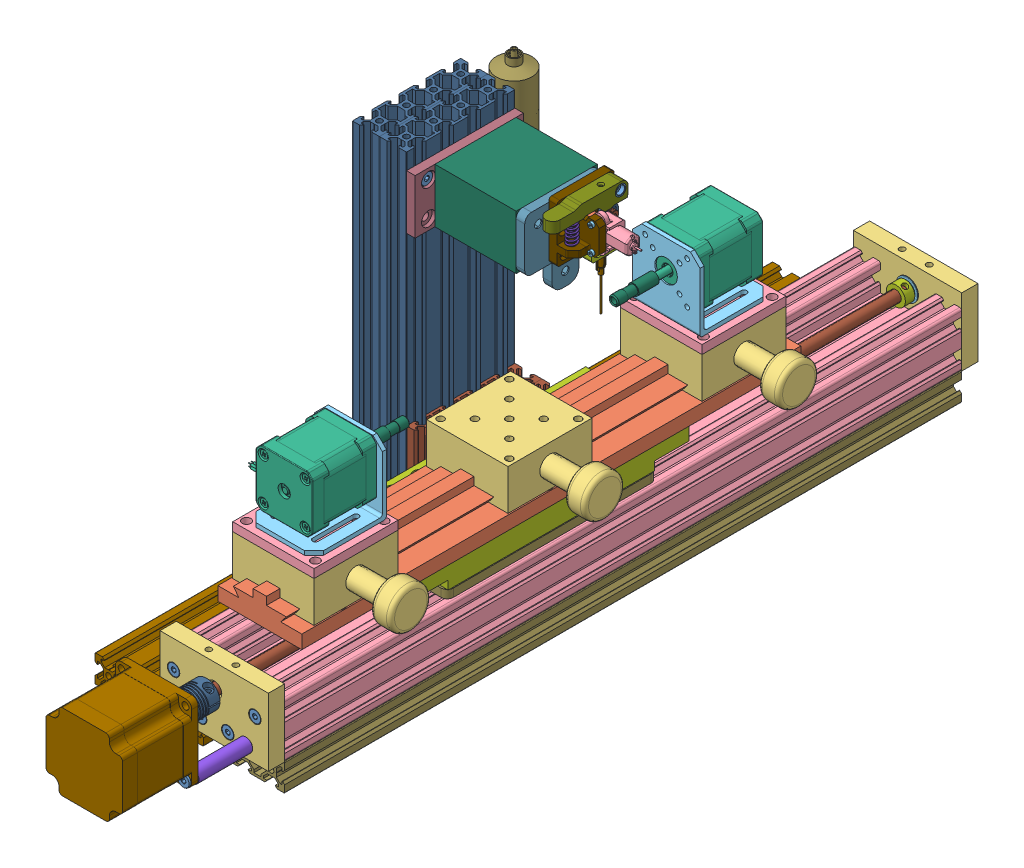
SolidWorks assembly LathePrinter, configuration Default. Lengths in mm.
Overall size (197.6 251.58 620.07).
127 component instances, 54 part files, 33 mates.
Components (placement in the parent):
- C-Beam Doublewide Linear Actuator 500mm-1: C-Beam Doublewide Linear Actuator 500mm [Default] at origin size (80 60.67 620.07)
  - Low Profile Screw M5-3: Low Profile Screw M5 [M5 x 20] at (56.4477 48.3418 46.5759) x (0 0 -1) z (1 0 0) size (21.62 9 9)
  - Low Profile Screw M5-4: Low Profile Screw M5 [M5 x 20] at (36.4477 28.3418 46.5759) x (0 0 -1) z (1 0 0) size (21.62 9 9)
  - Low Profile Screw M5-5: Low Profile Screw M5 [M5 x 20] at (16.4477 28.3418 46.5759) x (0 0 -1) z (1 0 0) size (21.62 9 9)
  - Low Profile Screw M5-6: Low Profile Screw M5 [M5 x 20] at (-3.5523 48.3418 46.5759) x (0 0 -1) z (1 0 0) size (21.62 9 9)
  - Low Profile Screw M5-7: Low Profile Screw M5 [M5 x 20] at (56.4477 48.3418 -434.3241) x (0 0 1) z (-1 0 0) size (21.62 9 9)
  - Low Profile Screw M5-8: Low Profile Screw M5 [M5 x 20] at (36.4477 28.3418 -434.3241) x (0 0 1) z (-1 0 0) size (21.62 9 9)
  - Low Profile Screw M5-9: Low Profile Screw M5 [M5 x 20] at (16.4477 28.3418 -434.3241) x (0 0 1) z (-1 0 0) size (21.62 9 9)
  - Low Profile Screw M5-10: Low Profile Screw M5 [M5 x 20] at (-3.5523 48.3418 -434.3241) x (0 0 1) z (-1 0 0) size (21.62 9 9)
  - Nylon Insert Lock Nut M5-1: Nylon Insert Lock Nut M5 [Default] at (36.4477 49.7418 -147.7451) x (0.5 0 0.866025) z (0.866025 0 -0.5) size (8 5 9.24)
  - Nylon Insert Lock Nut M5-2: Nylon Insert Lock Nut M5 [Default] at (16.4477 49.7418 -147.7451) x (-0.5 0 0.866025) z (0.866025 0 0.5) size (8 5 9.24)
  - Low Profile Screw M5-11: Low Profile Screw M5 [M5 x 20] at (16.4477 44.5418 -147.7451) x (0 -1 0) z (0 0 1) size (21.62 9 9)
  - Low Profile Screw M5-12: Low Profile Screw M5 [M5 x 20] at (36.4477 44.5418 -147.7451) x (0 -1 0) z (0 0 1) size (21.62 9 9)
  - Low Profile Screw M5-13: Low Profile Screw M5 [M5 x 25] at (40.6977 39.5418 -191.4751) x (0 -1 0) z (-0.551688 0 0.834051) size (26.62 9 9)
  - Low Profile Screw M5-14: Low Profile Screw M5 [M5 x 25] at (40.6977 39.5418 -93.9651) x (0 -1 0) z (-0.031752 0 0.999496) size (26.62 9 9)
  - Low Profile Screw M5-15: Low Profile Screw M5 [M5 x 25] at (12.1977 39.5418 -192.2651) x (0 -1 0) z (-0.003762 0 0.999993) size (26.62 9 9)
  - Low Profile Screw M5-16: Low Profile Screw M5 [M5 x 25] at (12.1977 39.5418 -93.1751) x (0 -1 0) z (-0.030252 0 0.999542) size (26.62 9 9)
  - Low Profile Screw M5-17: Low Profile Screw M5 [M5 x 55] at (50.0177 27.2418 57.9259) x (0 0 -1) z (1 0 0) size (56.62 9 9)
  - Low Profile Screw M5-18: Low Profile Screw M5 [M5 x 55] at (2.8777 27.2418 57.9259) x (0 0 -1) z (1 0 0) size (56.62 9 9)
  - C-Beam End Mount-1: C-Beam End Mount [Default] at (-13.5523 18.3418 56.1259) size (80 50 12)
  - C-Beam 40x80x500 Linear Rail-1: C-Beam 40x80x500 Linear Rail [Default] at (26.4477 38.3418 -443.8741) x (0 1 0) z (0 0 1) size (40 80 500)
  - C-Beam End Mount-2: C-Beam End Mount [Default] at (66.4477 18.3418 -443.8741) x (-1 0 0) z (0 0 -1) size (80 50 12)
  - Ball Bearing 8 x 16 x 5-1: Ball Bearing 8 x 16 x 5 [Default] at (26.4477 50.7418 -445.8741) x (0 0 1) z (-0.834564 -0.55091 0) size (5 16 16)
  - Ball Bearing 8 x 16 x 5-2: Ball Bearing 8 x 16 x 5 [Default] at (26.4477 50.7418 58.1259) x (0 0 -1) z (0.759688 -0.650288 0) size (5 16 16)
  - Shim Washer 8mm-1: Shim Washer 8mm [Default] at (26.4477 50.7418 -443.3741) x (0.747547 0.664209 0) z (0.664209 -0.747547 0) size (11.8 1.15 11.8)
  - Shim Washer 8mm-2: Shim Washer 8mm [Default] at (26.4477 50.7418 54.4759) x (0.999066 -0.043208 0) z (-0.043208 -0.999066 0) size (11.8 1.15 11.8)
  - Lock Collar 8mm-1: Lock Collar 8mm [Default] at (26.4477 50.7418 -442.2241) x (0.884083 -0.467331 0) z (0 0 1) size (14 14 7)
  - Lock Collar 8mm-2: Lock Collar 8mm [Default] at (26.4477 50.7418 47.4759) x (0.923513 -0.383568 0) z (0 0 1) size (14 14 7)
  - Aluminum Spacer 40mm-1: Aluminum Spacer 40mm [Default] at (2.8777 27.2418 68.1259) size (10 10 40)
  - Aluminum Spacer 40mm-2: Aluminum Spacer 40mm [Default] at (50.0177 27.2418 68.1259) x (0.999611 0.027877 0) z (0 0 1) size (10 10 40)
  - Nema 23 Stepper Motor-1: Nema 23 Stepper Motor [Default] at (26.4477 50.8118 108.1259) x (-1 0 0) z (0 0 -1) size (56.4 56.4 76.6)
  - Flexible Coupling 0.25in x 8mm-1: Flexible Coupling 0.25in x 8mm [Default] at (26.4477 50.8118 98.5259) size (21.03 20 25)
  - 8mm leadscrew 540mm-1: 8mm leadscrew 540mm [Default] at (26.4477 50.7418 -455.8741) size (8 8 540)
  - Double CB-Gantry Plate-1: Double CB-Gantry Plate [Default] at (65.2077 60.0418 -65.2101) x (0 0 -1) z (1 0 0) size (155.02 6 77.52)
  - 8mm Acme Nut Block-1: 8mm Acme Nut Block [Default] at (26.4477 50.7418 -137.7451) x (1 0 0) z (0 0 -1) size (34 12 20)
  - Xtreme Mini V Wheel-1: Xtreme Mini V Wheel [Straight] at (40.6977 48.3418 -93.9651) x (0.579004 0 0.815325) z (-0.815325 0 0.579004) size (15.23 23.9 15.23)
    - Xtreme Mini V Wheel-1: Xtreme Mini V Wheel [Default] x (0 -1 0) z (0 0 1) size (8.8 15.23 15.23)
    - Ball Bearing 5 x 10 x 4.2-1: Ball Bearing 5 x 10 x 4.2 [Default] at (0 -2.6 0) x (0 -1 0) z (0.990411 0 0.138155) size (4.2 10 10)
    - Ball Bearing 5 x 10 x 4.2-2: Ball Bearing 5 x 10 x 4.2 [Default] at (0 2.6 0) x (0 1 0) z (-0.887666 0 -0.460488) size (4.2 10 10)
    - Precision Shim 8 x 5 x 1-1: Precision Shim 8 x 5 x 1 [Default] at (0 -0.5 0) x (0.977063 0 -0.212952) z (0.212952 0 0.977063) size (8 1 8)
    - Precision Shim 8 x 5 x 1-2: Precision Shim 8 x 5 x 1 [Default] at (0 4.7 0) x (0.633048 0 -0.774113) z (0.774113 0 0.633048) size (8 1 8)
    - Nylon Insert Lock Nut M5-1: Nylon Insert Lock Nut M5 [Default] at (0 -4.7 0) x (-0.212185 0 -0.97723) z (-0.97723 0 0.212185) size (8 5 9.24)
    - Mini Eccentric Spacer 6mm-1: Mini Eccentric Spacer 6mm [Default] at (-0.79 10.7 0) x (0 0 1) z (1 0 0) size (10 8.5 9.7)
    - Aluminum Spacer 6mm-1: Aluminum Spacer 6mm [Default] at (0 11.7 0) x (-0.695188 0 0.718828) z (0 -1 0) size (10 10 6)
  - Xtreme Mini V Wheel-2: Xtreme Mini V Wheel [Straight] at (40.6977 48.3418 -191.4751) x (0.579004 0 0.815325) z (-0.815325 0 0.579004) size (15.23 23.9 15.23)
    - Xtreme Mini V Wheel-1: Xtreme Mini V Wheel [Default] x (0 -1 0) z (0 0 1) size (8.8 15.23 15.23)
    - Ball Bearing 5 x 10 x 4.2-1: Ball Bearing 5 x 10 x 4.2 [Default] at (0 -2.6 0) x (0 -1 0) z (0.990411 0 0.138155) size (4.2 10 10)
    - Ball Bearing 5 x 10 x 4.2-2: Ball Bearing 5 x 10 x 4.2 [Default] at (0 2.6 0) x (0 1 0) z (-0.887666 0 -0.460488) size (4.2 10 10)
    - Precision Shim 8 x 5 x 1-1: Precision Shim 8 x 5 x 1 [Default] at (0 -0.5 0) x (0.977063 0 -0.212952) z (0.212952 0 0.977063) size (8 1 8)
    - Precision Shim 8 x 5 x 1-2: Precision Shim 8 x 5 x 1 [Default] at (0 4.7 0) x (0.633048 0 -0.774113) z (0.774113 0 0.633048) size (8 1 8)
    - Nylon Insert Lock Nut M5-1: Nylon Insert Lock Nut M5 [Default] at (0 -4.7 0) x (-0.212185 0 -0.97723) z (-0.97723 0 0.212185) size (8 5 9.24)
    - Mini Eccentric Spacer 6mm-1: Mini Eccentric Spacer 6mm [Default] at (-0.79 10.7 0) x (0 0 1) z (1 0 0) size (10 8.5 9.7)
    - Aluminum Spacer 6mm-1: Aluminum Spacer 6mm [Default] at (0 11.7 0) x (-0.695188 0 0.718828) z (0 -1 0) size (10 10 6)
  - Xtreme Mini V Wheel-3: Xtreme Mini V Wheel [Eccentric] at (12.1977 48.3418 -93.1751) x (0 0 1) z (-1 0 0) size (15.23 23.9 15.23)
    - Xtreme Mini V Wheel-1: Xtreme Mini V Wheel [Default] x (0 -1 0) z (0 0 1) size (8.8 15.23 15.23)
    - Ball Bearing 5 x 10 x 4.2-1: Ball Bearing 5 x 10 x 4.2 [Default] at (0 -2.6 0) x (0 -1 0) z (0.990411 0 0.138155) size (4.2 10 10)
    - Ball Bearing 5 x 10 x 4.2-2: Ball Bearing 5 x 10 x 4.2 [Default] at (0 2.6 0) x (0 1 0) z (-0.887666 0 -0.460488) size (4.2 10 10)
    - Precision Shim 8 x 5 x 1-1: Precision Shim 8 x 5 x 1 [Default] at (0 -0.5 0) x (0.977063 0 -0.212952) z (0.212952 0 0.977063) size (8 1 8)
    - Precision Shim 8 x 5 x 1-2: Precision Shim 8 x 5 x 1 [Default] at (0 4.7 0) x (0.633048 0 -0.774113) z (0.774113 0 0.633048) size (8 1 8)
    - Nylon Insert Lock Nut M5-1: Nylon Insert Lock Nut M5 [Default] at (0 -4.7 0) x (-0.212185 0 -0.97723) z (-0.97723 0 0.212185) size (8 5 9.24)
    - Mini Eccentric Spacer 6mm-1: Mini Eccentric Spacer 6mm [Default] at (-0.79 10.7 0) x (0 0 1) z (1 0 0) size (10 8.5 9.7)
    - Aluminum Spacer 6mm-1: Aluminum Spacer 6mm [Default] at (0 11.7 0) x (-0.695188 0 0.718828) z (0 -1 0) size (10 10 6)
  - Xtreme Mini V Wheel-4: Xtreme Mini V Wheel [Eccentric] at (12.1977 48.3418 -192.2651) x (0 0 -1) z (1 0 0) size (15.23 23.9 15.23)
    - Xtreme Mini V Wheel-1: Xtreme Mini V Wheel [Default] x (0 -1 0) z (0 0 1) size (8.8 15.23 15.23)
    - Ball Bearing 5 x 10 x 4.2-1: Ball Bearing 5 x 10 x 4.2 [Default] at (0 -2.6 0) x (0 -1 0) z (0.990411 0 0.138155) size (4.2 10 10)
    - Ball Bearing 5 x 10 x 4.2-2: Ball Bearing 5 x 10 x 4.2 [Default] at (0 2.6 0) x (0 1 0) z (-0.887666 0 -0.460488) size (4.2 10 10)
    - Precision Shim 8 x 5 x 1-1: Precision Shim 8 x 5 x 1 [Default] at (0 -0.5 0) x (0.977063 0 -0.212952) z (0.212952 0 0.977063) size (8 1 8)
    - Precision Shim 8 x 5 x 1-2: Precision Shim 8 x 5 x 1 [Default] at (0 4.7 0) x (0.633048 0 -0.774113) z (0.774113 0 0.633048) size (8 1 8)
    - Nylon Insert Lock Nut M5-1: Nylon Insert Lock Nut M5 [Default] at (0 -4.7 0) x (-0.212185 0 -0.97723) z (-0.97723 0 0.212185) size (8 5 9.24)
    - Mini Eccentric Spacer 6mm-1: Mini Eccentric Spacer 6mm [Default] at (-0.79 10.7 0) x (0 0 1) z (1 0 0) size (10 8.5 9.7)
    - Aluminum Spacer 6mm-1: Aluminum Spacer 6mm [Default] at (0 11.7 0) x (-0.695188 0 0.718828) z (0 -1 0) size (10 10 6)
  - Aluminum Spacer 3mm-1: Aluminum Spacer 3mm [Default] at (36.4477 57.0418 -147.7451) x (0.737978 0 0.674825) z (0 1 0) size (10 10 3)
  - Aluminum Spacer 3mm-2: Aluminum Spacer 3mm [Default] at (16.4477 57.0418 -147.7451) x (0.756365 0 -0.654149) z (0 1 0) size (10 10 3)
- Z Carriage Assembly-1: Z Carriage Assembly [Default] at (324.4062 -89.9257 -277.865) x (0 0 1) z (-1 0 0) size (368.5 98.11 101.5)
  - Edmund Optics Linear Bearing-1: Edmund Optics Linear Bearing [Default] at (-49.1052 171.8424 290.8585) size (368.5 21.1 62)
  - Edmund Optics Knob Stage-1: Edmund Optics Knob Stage [Default] at (-8.1052 211.8424 290.8585) x (0 0 -1) z (0 -1 0) size (100.5 62 30)
  - Edmund Optics Knob Stage-4: Edmund Optics Knob Stage [Default] at (135.1448 211.8424 290.8585) x (0 0 -1) z (0 -1 0) size (100.5 62 30)
  - Edmund Optics Knob Stage-5: Edmund Optics Knob Stage [Default] at (278.3948 211.8424 290.8585) x (0 0 -1) z (0 -1 0) size (100.5 62 30)
  - Mandrel Motor Plate-1: Mandrel Motor Plate [Default] at (278.3948 211.8424 290.8585) x (0 0 -1) z (0 1 0) size (60 62 6.35)
  - Mandrel Motor Plate-2: Mandrel Motor Plate [Default] at (-8.1052 211.8424 290.8585) x (0 0 -1) z (0 1 0) size (60 62 6.35)
  - Mandrel Motor Bracket-1: Mandrel Motor Bracket [Default] at (250.8948 218.1924 265.8585) size (53.5 51.5 50)
  - Mandrel Motor Bracket-2: Mandrel Motor Bracket [Default] at (19.3948 218.1924 315.8585) x (-1 0 0) z (0 0 -1) size (53.5 51.5 50)
  - NEMA17 Stepper-1: NEMA17 Stepper [По умолчанию] at (301.3948 235.6273 292.556) x (0 0.999984 -0.005702) z (0 0.005702 0.999984) size (42.19 71.6 51.3)
  - NEMA17 Stepper-2: NEMA17 Stepper [По умолчанию] at (-31.1052 261.7575 292.556) x (0 -0.999984 -0.005702) z (0 -0.005702 0.999984) size (42.19 71.6 51.3)
- Z Axis Plate-1: Z Axis Plate [Default] at (26.4477 66.0418 -142.7201) x (0 0 1) z (-1 0 0) size (203.2 15.88 76.2)
- 94855A247_LOW-STRENGTH STEEL SQUARE NUT-1: 94855A247_LOW-STRENGTH STEEL SQUARE NUT [94855A247] at (8.1553 70.0105 -141.8396) x (0.999789 0 0.020564) z (-0.020564 0 0.999789) size (11.11 5.74 11.11)
- Aluminum Extrusion Frame-1: Aluminum Extrusion Frame [Default] at (-183.5863 -1.6582 -193.8741) x (0 0 -1) z (1 0 0) size (500 245 160)
  - V-Slot 20x80x500 Linear Rail-1: V-Slot 20x80x500 Linear Rail [Default] at (250 10 150.034) x (0 -1 0) z (-1 0 0) size (20 80 500)
  - V-Slot 20x80x225 Linear Rail-2: V-Slot 20x80x225 Linear Rail [Default] at (0 245 100.034) x (0 0 1) z (0 -1 0) size (20 80 225)
  - V-Slot 20x80x225 Linear Rail-3: V-Slot 20x80x225 Linear Rail [Default] at (0 245 120.034) x (0 0 1) z (0 -1 0) size (20 80 225)
  - V-Slot 20x80x50 Linear Rail-4: V-Slot 20x80x50 Linear Rail [Default] at (0 70 140.034) x (0 0 1) z (0 -1 0) size (20 80 50)
  - V-Slot 20x40x500 Linear Rail-1: V-Slot 20x40x500 Linear Rail [Default] at (250 10 230.034) x (0 1 0) z (-1 0 0) size (20 40 500)
  - V-Slot 20x80x50 Linear Rail-5: V-Slot 20x80x50 Linear Rail [Default] at (0 70 160.034) x (0 0 1) z (0 -1 0) size (20 80 50)
- X Axis Plate-1: X Axis Plate [Default] at (-53.5523 211.4905 -193.8741) x (0 0 1) z (0 1 0) size (80 6.35 40)
- Low Profile Screw M5-1: Low Profile Screw M5 [M5 x 20] at (-69.9523 223.9905 -163.8741) x (-1 0 0) z (0 0.410028 -0.912073) size (21.62 9 9)
- Low Profile Screw M5-2: Low Profile Screw M5 [M5 x 20] at (56.4477 56.8168 -93.9651) x (0 -1 0) z (0 0 1) size (21.62 9 9)
- Nozzle Plate-1: Nozzle Plate [Captive nuts] at (12.7977 191.4905 -168.4783) x (0 0 -1) z (1 0 0) size (60 60 6.35)
- Optics XZ Manual Stage Placeholder-1: Optics XZ Manual Stage Placeholder [Default] at (-47.2023 211.4905 -193.8741) x (0 0 1) z (1 0 0) size (60 40 60)
- Experimental Extruder Dual Extruder-1: Experimental Extruder Dual Extruder [Default] at (19.1477 213.6163 -207.3751) x (0 0 -1) z (1 0 0) size (131.31 82.59 47.28)
  - ExtruderCR10 lever mirrored-1: ExtruderCR10 lever mirrored [Default] at (-21 -21 2) size (55.67 26.5 10.5)
  - ExtruderCR10 spring-1: ExtruderCR10 spring [Default] at (-21 -21 1.5) size (8.03 21.41 8.04)
  - Extruder custom base mirrored-1: Extruder custom base mirrored [Default] at origin size (42 42 26)
  - ExtruderCR10 bushing-1: ExtruderCR10 bushing [Default] at (-21 -21 2) size (8 8 10.5)
  - SLA Printed Driver-1: SLA Printed Driver [Default] at (0 0 -17.7668) size (11.5 11.5 6)
  - 52335K910 TUBING MADE WITH PTFE cut to size-1: 52335K910 TUBING MADE WITH PTFE cut to size [52335K91] at (6.35 -9.5 11) x (0 1 0) z (0.546944 0 -0.837169) size (15 3 3)
  - micro-metal-gearmotor-extended-with-1086-bracket (1)-1: micro-metal-gearmotor-extended-with-1086-bracket (1) [Default] at (0 0 26.27) x (0 0 -1) z (0 -1 0) size (39.3 11.72 26.5)
  - 91290A015_BLACK-OXIDE CLASS 12.9 SOCKET HEAD CAP SCREW-1: 91290A015_BLACK-OXIDE CLASS 12.9 SOCKET HEAD CAP SCREW [91290A015] at (-2 -9 21.2) x (0 -0.941673 -0.336529) z (1 0 0) size (3.8 3.8 10.11)
  - 91290A015_BLACK-OXIDE CLASS 12.9 SOCKET HEAD CAP SCREW-2: 91290A015_BLACK-OXIDE CLASS 12.9 SOCKET HEAD CAP SCREW [91290A015] at (-2 9 21.2) x (0 -0.660306 0.750996) z (1 0 0) size (3.8 3.8 10.11)
  - 91828A111_TYPE 18-8 STAINLESS STEEL HEX NUT-1: 91828A111_TYPE 18-8 STAINLESS STEEL HEX NUT [91828A111] at (-2.8 9 21.2) x (0 0 1) z (-1 0 0) size (4 4.62 1.83)
  - SLA Printed Manifold-1: SLA Printed Manifold [Default] at origin size (27 14.5 10.5)
  - Luer male print with manifold-2: Luer male print with manifold [Default] at (17.8808 -9.5965 11) x (0.923028 0.384734 0) z (0 0 1) size (8.55 9.27 9.27)
  - Luer male print with manifold-3: Luer male print with manifold [Default] at (6.35 -25.5471 11) x (0 -1 0) z (0 0 1) size (8.55 9.27 9.27)
  - Syringe Needle, With Luer-2: Syringe Needle, With Luer [Yellow_20Gauge] at (6.35 -36.1851 11) x (0 1 0) z (0 0 1) size (43.15 7.7 8.15)
  - MirrorExtruder custom base-2: MirrorExtruder custom base [Default] at (62 0 0) x (-1 0 0) z (0 0 -1) size (42 42 26) (hidden)
  - MirrorExtruderCR10 lever-2: MirrorExtruderCR10 lever [Default] at (83 -21 2) x (-1 0 0) z (0 0 -1) size (55.67 26.5 10.5) (hidden)
  - ExtruderCR10 bushing-2: ExtruderCR10 bushing [Default] at (10 -21 2) size (8 8 10.5) (hidden)
  - Luer male print with manifold-5: Luer male print with manifold [Default] at (44.1192 -9.5965 11) x (-0.923028 0.384734 0) z (0 0 1) size (8.55 9.27 9.27) (hidden)
  - MirrorPart21-2: MirrorPart21 [Default] at (62 0 0) x (-1 0 0) z (0 0 -1) size (27 14.5 10.5) (hidden)
  - Luer male print with manifold-6: Luer male print with manifold [Default] at (55.65 -25.5471 11) x (0 -1 0) z (0 0 -1) size (8.55 9.27 9.27) (hidden)
  - 7804K102_STAINLESS STEEL BALL BEARING-1: 7804K102_STAINLESS STEEL BALL BEARING [7804K102] at (11.6075 1 11) x (0.999251 0.038691 0) z (0 0 1) size (12 12 4)
  - 91273A351_SAME-SIZE THREAD 18-8 SS SHOULDER SCREW-1: 91273A351_SAME-SIZE THREAD 18-8 SS SHOULDER SCREW [91273A351] at (11.6075 1 16) x (0.991631 -0.129104 0) z (0 0 1) size (6 6 11.85)
- 014-0244 35cc Syringe-1: 014-0244 35cc Syringe [Default] at (-73.6051 249.9175 -253.3116) x (0 1 0) z (0 0 1) size (127.38 29.39 34.92)
  - 014-0244 ITEM1 Barrel-1: 014-0244 ITEM1 Barrel [Default] at origin size (116.46 29.39 34.92)
  - 014-0244 ITEM2 Plunger-1: 014-0244 ITEM2 Plunger [Default] at (-127.381 0 0) size (113.82 29.21 29.21)
  - 014-0244 ITEM3 Gasket-1: 014-0244 ITEM3 Gasket [Default] at (-20.701 0 0) size (11.43 24.13 24.13)
- Dremel collet 9_32 - 40 threads-1: Dremel collet 9_32 - 40 threads [Default] at (33.5477 158.7668 -36.0701) x (0 0 -1) z (-0.463704 0.88599 0) size (30 8 8)
- Dremel collet 9_32 - 40 threads-2: Dremel collet 9_32 - 40 threads [Default] at (33.5477 158.7668 -249.3701) x (0 0 1) z (0.953051 -0.302808 0) size (30 8 8)
Mates (geometry in assembly coordinates):
- Coincident1: coincident anti-aligned: plane of C-Beam Doublewide Linear Actuator 500mm-1/Double CB-Gantry Plate-1 through (60.5677 66.0418 -215.5901) normal (0 1 0); plane of Y Interface Plate^LathePrinter-1 through (26.4477 66.0418 -142.7201) normal (0 -1 0)
- Width1: width anti-aligned: plane of Y Interface Plate^LathePrinter-1 through (-11.6523 81.9168 -41.1201) normal (0 0 1); plane of C-Beam Doublewide Linear Actuator 500mm-1/Double CB-Gantry Plate-1 through (-11.6523 81.9168 -244.3201) normal (0 0 -1); plane of Y Interface Plate^LathePrinter-1 through (60.5677 66.0418 -220.2301) normal (0 0 -1); plane of C-Beam Doublewide Linear Actuator 500mm-1/Double CB-Gantry Plate-1 through (60.5677 66.0418 -65.2101) normal (0 0 1)
- Width2: width aligned: plane of Y Interface Plate^LathePrinter-1 through (64.5477 81.9168 -244.3201) normal (1 0 0); plane of C-Beam Doublewide Linear Actuator 500mm-1/Double CB-Gantry Plate-1 through (-11.6523 81.9168 -244.3201) normal (-1 0 0); plane of Y Interface Plate^LathePrinter-1 through (65.2077 66.0418 -69.8501) normal (1 0 0); plane of C-Beam Doublewide Linear Actuator 500mm-1/Double CB-Gantry Plate-1 through (-12.3123 66.0418 -69.8501) normal (-1 0 0)
- Coincident2: coincident anti-aligned: plane of Y Carriage-1/Edmund Optics Linear Bearing-1 through (2.5477 81.9168 41.5299) normal (0 -1 0); plane of Y Interface Plate^LathePrinter-1 through (26.4477 81.9168 -142.7201) normal (0 1 0)
- Coincident3: coincident aligned: plane of Y Carriage-1/Edmund Optics Linear Bearing-1 through (64.5477 81.9168 41.5299) normal (1 0 0); plane of Y Interface Plate^LathePrinter-1 through (64.5477 81.9168 -244.3201) normal (1 0 0)
- Width3: width anti-aligned: plane of Y Carriage-1/Edmund Optics Linear Bearing-1 through (33.5477 81.9168 -326.9701) normal (0 0 -1); plane of Y Interface Plate^LathePrinter-1 through (33.5477 81.9168 41.5299) normal (0 0 1); plane of Y Carriage-1/Edmund Optics Linear Bearing-1 through (-11.6523 81.9168 -41.1201) normal (0 0 1); plane of Y Interface Plate^LathePrinter-1 through (-11.6523 81.9168 -244.3201) normal (0 0 -1)
- Coincident4: coincident anti-aligned: plane of Y Interface Plate^LathePrinter-1 through (34.0358 72.3918 -137.7648) normal (0 -1 0); plane of 94855A247_LOW-STRENGTH STEEL SQUARE NUT-1 through (2.486 72.3918 -136.3988) normal (0 1 0)
- Slot1: slot aligned: line of 94855A247_LOW-STRENGTH STEEL SQUARE NUT-1 through (8.1553 72.3918 -141.8396) axis (0 1 0); cylinder of Z Axis Plate-1 through (58.9477 66.0418 -142.7201) axis (0 1 0) radius 54.1734; cylinder of Z Axis Plate-1 through (8.341 66.0418 -138.2926) axis (0 1 0) radius 3.3734
- Coincident6: coincident aligned: plane of C-Beam Doublewide Linear Actuator 500mm-1/C-Beam 40x80x500 Linear Rail-1 through (26.4477 38.3418 -443.8741) normal (0 0 -1); plane of Frame-1/V-Slot 20x80x500 Linear Rail-1 through (-33.5523 8.3418 -443.8741) normal (0 0 -1)
- Coincident8: coincident anti-aligned: plane of C-Beam Doublewide Linear Actuator 500mm-1/C-Beam 40x80x500 Linear Rail-1 through (26.4477 18.3418 56.1259) normal (0 -1 0); plane of Frame-1/V-Slot 20x80x500 Linear Rail-1 through (-33.5523 18.3418 56.1259) normal (0 1 0)
- Coincident9: coincident anti-aligned: plane of Frame-1/V-Slot 20x80x225 Linear Rail-3 through (-53.5523 18.3418 -193.8741) normal (1 0 0); plane of X Interface Plate^LathePrinter-1 through (-53.5523 211.4905 -193.8741) normal (-1 0 0)
- Width4: width anti-aligned: plane of X Interface Plate^LathePrinter-1 through (-47.2023 231.4905 -153.8741) normal (0 0 1); plane of Frame-1/V-Slot 20x80x50 Linear Rail-4 through (-47.2023 231.4905 -233.8741) normal (0 0 -1); plane of X Interface Plate^LathePrinter-1 through (-43.5523 18.3418 -233.8741) normal (0 0 -1); plane of Frame-1/V-Slot 20x80x50 Linear Rail-4 through (-43.5523 18.3418 -153.8741) normal (0 0 1)
- Concentric1: concentric anti-aligned: cylinder of X Interface Plate^LathePrinter-1 through (-47.2023 223.9905 -163.8741) axis (1 0 0) radius 2.75; cylinder of Low Profile Screw M5-1 through (-49.9523 223.9905 -163.8741) axis (-1 0 0) radius 2.5
- Coincident10: coincident anti-aligned: plane of X Interface Plate^LathePrinter-1 through (-49.9523 223.9905 -161.1241) normal (1 0 0); plane of Low Profile Screw M5-1 through (-49.9523 227.786 -162.1678) normal (-1 0 0)
- Concentric2: concentric anti-aligned: cylinder of Y Interface Plate^LathePrinter-1 through (56.4477 81.9168 -93.9651) axis (0 1 0) radius 2.75; cylinder of Low Profile Screw M5-2 through (56.4477 76.8168 -93.9651) axis (0 -1 0) radius 2.5
- Coincident11: coincident anti-aligned: plane of Y Interface Plate^LathePrinter-1 through (56.4477 76.8168 -91.2151) normal (0 1 0); plane of Low Profile Screw M5-2 through (60.6091 76.8168 -93.9651) normal (0 -1 0)
- Parallel1: parallel anti-aligned: plane of X Interface Plate-1 through (-47.2023 211.4905 -193.8741) normal (1 0 0); plane of CR-10 Bracket Mount-1 through (12.7977 196.4905 -173.4783) normal (-1 0 0)
- Coincident13: coincident aligned: plane of C-Beam Doublewide Linear Actuator 500mm-1/C-Beam 40x80x500 Linear Rail-1 through (66.4477 38.3418 56.1259) normal (1 0 0); plane of Frame-1/V-Slot 20x40x500 Linear Rail-1 through (66.4477 8.3418 56.1259) normal (1 0 0)
- InPlace1: in place: plane of ? through (-47.2023 211.0544 -193.8741) normal (1 0 0); plane of ? through (-47.2023 0 0) normal (1 0 0); moOrthogonalPlaneRef_w of ? through (-47.2023 211.0544 -193.8741) normal (1 0 0); plane of ? through (-47.2023 0 0) normal (0 1 0); plane of ? through (-47.2023 211.0544 -193.8741) normal (1 0 0); plane of ? through (-47.2023 0 0) normal (0 0 -1); plane of X Axis Plate-1 through (-47.2023 211.4905 -193.8741) normal (1 0 0); unknown of Optics XZ Manual Stage Placeholder-1
- Coincident14: coincident aligned: plane of ?; plane of ?
- Coincident15: coincident aligned: moOrthogonalPlaneRef_w of X Interface Plate-1 through (-47.2023 211.4905 -193.8741) normal (0 -1 0); plane of Part1^LathePrinter-1 through (-47.2023 211.4905 -193.8741) normal (0 -1 0)
- Coincident16: coincident anti-aligned: moOrthogonalPlaneRef_w of X Interface Plate-1 through (-47.2023 211.4905 -193.8741) normal (0 0 -1); plane of Part1^LathePrinter-1 through (-47.2023 211.4905 -193.8741) normal (0 0 1)
- Coincident17: coincident anti-aligned: plane of CR-10 Bracket Mount-1 through (12.7977 196.4905 -173.4783) normal (-1 0 0); plane of Optics XZ Placeholder^LathePrinter-1 through (12.7977 211.4905 -193.8741) normal (1 0 0)
- Width5: width anti-aligned: plane of CR-10 Bracket Mount-1 through (19.1477 196.4905 -168.4783) normal (0 0 1); plane of CR-10 Bracket Mount-1 through (19.1477 196.4905 -228.4783) normal (0 0 -1); plane of Optics XZ Placeholder^LathePrinter-1 through (12.7977 191.4905 -228.4783) normal (0 0 -1); plane of Optics XZ Placeholder^LathePrinter-1 through (12.7977 191.4905 -168.4783) normal (0 0 1)
- Width6: width anti-aligned: plane of CR-10 Bracket Mount-1 through (19.1477 231.4905 -173.4783) normal (0 1 0); plane of CR-10 Bracket Mount-1 through (19.1477 191.4905 -173.4783) normal (0 -1 0); plane of Optics XZ Placeholder^LathePrinter-1 through (12.7977 191.4905 -168.4783) normal (0 -1 0); plane of Optics XZ Placeholder^LathePrinter-1 through (12.7977 231.4905 -168.4783) normal (0 1 0)
- Parallel2: parallel anti-aligned: plane of 014-0244 35cc Syringe-1 through (-73.6051 249.9175 -253.3116) normal (-1 0 0)
- Coincident18: coincident anti-aligned: plane of CR-10 Bracket Mount-1 through (19.1477 196.4905 -173.4783) normal (1 0 0); plane of Extruder mini gear motor custom-1/Extruder custom base-1 through (19.1477 213.6163 -207.3751) normal (-1 0 0)
- Parallel3: parallel aligned: plane of CR-10 Bracket Mount-1 through (19.1477 231.4905 -173.4783) normal (0 1 0); plane of Extruder mini gear motor custom-1/Extruder custom base-1 through (25.1477 234.6163 -186.3751) normal (0 1 0)
- Concentric4: concentric aligned: cylinder of CR-10 Bracket Mount-1 through (19.1477 198.1163 -222.8751) axis (1 0 0) radius 1.7; cylinder of Extruder mini gear motor custom-1/Extruder custom base-1 through (25.1477 198.1163 -222.8751) axis (1 0 0) radius 1.7
- Concentric5: concentric aligned: cylinder of Z Carriage Assembly-1/NEMA17 Stepper-1 through (33.5477 158.7668 -48.0701) axis (0 0 1) radius 2.5; cylinder of Dremel collet no threads-1 through (33.5477 158.7668 -48.0701) axis (0 0 1) radius 2.5
- Coincident19: coincident anti-aligned: plane of Z Carriage Assembly-1/NEMA17 Stepper-1 through (33.5477 158.7668 -48.0701) normal (0 0 -1); plane of Dremel collet no threads-1 through (33.5477 158.7668 -48.0701) normal (0 0 1)
- Concentric6: concentric aligned: cylinder of Z Carriage Assembly-1/NEMA17 Stepper-2 through (33.5477 158.7668 -237.3701) axis (0 0 -1) radius 2.5; cylinder of Dremel collet 9_32 - 40 threads-2 through (33.5477 158.7668 -237.3701) axis (0 0 -1) radius 2.5
- Coincident20: coincident anti-aligned: plane of Z Carriage Assembly-1/NEMA17 Stepper-2 through (33.5477 158.7668 -237.3701) normal (0 0 1); plane of Dremel collet 9_32 - 40 threads-2 through (33.5477 158.7668 -237.3701) normal (0 0 -1)
